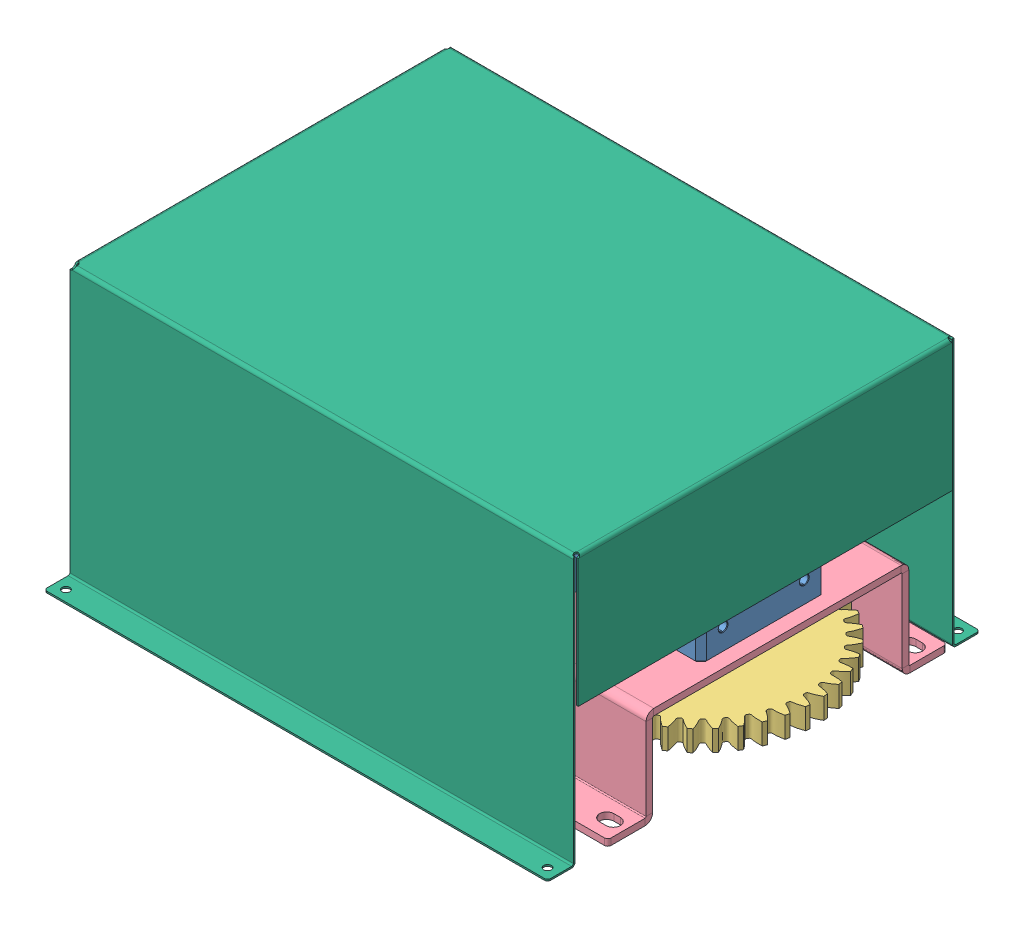
SolidWorks assembly assem gearbox, configuration Default. Lengths in mm.
Overall size (510.3 246.5 395).
7 component instances, 6 part files, 11 mates.
Components (placement in the parent):
- assem WS120F - HC SFS152-1: assem WS120F - HC SFS152 [Default] at (59.7007 381.3395 0) x (1 0 0) z (0 -1 0) size (429.7 193.51 173.52)
  - WS120F grearbox-1: WS120F grearbox [Default] at origin size (259.7 165.02 173.52)
  - HC SFS 152-2: HC SFS 152 [Default] at (-147.201 0 61) x (0 0 1) z (1 0 0) size (130 176 225)
- gearbox gear-1: gearbox gear [GearTrax] at (59.7007 219.8156 0) x (0.989604 0 0.143817) z (0 1 0) size (209.62 209.62 39.05)
- gearbox base-1: gearbox base [Default] at (129.7007 179.8395 -155) x (0 0 1) z (-1 0 0) size (310 89 190)
- servo shaft 24-2: servo shaft 24 [Default] at (59.7007 190.2906 0) x (0.919459 0 -0.393186) z (0.393186 0 0.919459) size (24 190 24)
- gearbox housing-1: gearbox housing [Default] at (129.7007 173.8395 12.5) x (0 0 -1) z (1 0 0) size (395 246.5 463.01)
Mates (geometry in assembly coordinates):
- Concentric1: concentric anti-aligned: cylinder of Rap hop so WS120F - HC SFS152-1/hop so WS120F-1 through (59.7007 229.3406 0) axis (0 -1 0) radius 12; cylinder of banh rang hop so v2-1 through (59.7007 219.8156 0) axis (0 1 0) radius 12
- Coincident1: coincident anti-aligned: plane of Rap hop so WS120F - HC SFS152-1/hop so WS120F-1 through (89.7007 229.3406 0) normal (0 -1 0); plane of banh rang hop so v2-1 through (59.7007 229.3406 0) normal (0 1 0)
- Coincident4: coincident anti-aligned: plane of Rap hop so WS120F - HC SFS152-1/hop so WS120F-1 through (59.7007 262.8395 0) normal (0 -1 0); plane of chan de hop so_v3-1 through (-60.2993 262.8395 -120) normal (0 1 0)
- Concentric2: concentric anti-aligned: cylinder of Rap hop so WS120F - HC SFS152-1/hop so WS120F-1 through (59.7007 262.8395 0) axis (0 -1 0) radius 55; cylinder of chan de hop so_v3-1 through (59.7007 173.8385 0) axis (0 1 0) radius 55.1
- Concentric3: concentric anti-aligned: cylinder of Rap hop so WS120F - HC SFS152-1/hop so WS120F-1 through (105.6627 262.8395 45.9619) axis (0 -1 0) radius 4; cylinder of chan de hop so_v3-1 through (105.6627 173.8385 45.9619) axis (0 1 0) radius 4.1
- Concentric4: concentric anti-aligned: cylinder of banh rang hop so v2-1 through (59.7007 219.8156 0) axis (0 1 0) radius 12; cylinder of cot servo 24-2 through (59.7007 380.2906 0) axis (0 -1 0) radius 12
- Coincident5: coincident anti-aligned: circle of banh rang hop so v2-1; plane of cot servo 24-2 through (59.7007 190.2906 0) normal (0 -1 0)
- Coincident6: coincident aligned: plane of chan de hop so_v3-1 through (-60.2993 173.8395 120) normal (0 -1 0); plane of hop che hop so-1 through (-330.2993 173.8395 185) normal (0 -1 0)
- Coincident8: coincident anti-aligned: plane of chan de hop so_v3-1 through (129.7007 173.8395 121) normal (1 0 0); plane of hop che hop so-1 through (129.7007 173.8395 12.5) normal (-1 0 0)
- Distance1: distance = 5 mm anti-aligned: plane of hop che hop so-1 through (-330.2993 418.8395 -160) normal (0 0 1); plane of chan de hop so_v3-1 through (-60.2993 173.8395 -155) normal (0 0 -1)
- Coincident10: coincident aligned: plane of Rap hop so WS120F - HC SFS152-1 through (59.7007 381.3395 0) normal (0 0 1); plane of assembly through (0 0 0) normal (0 0 1)
